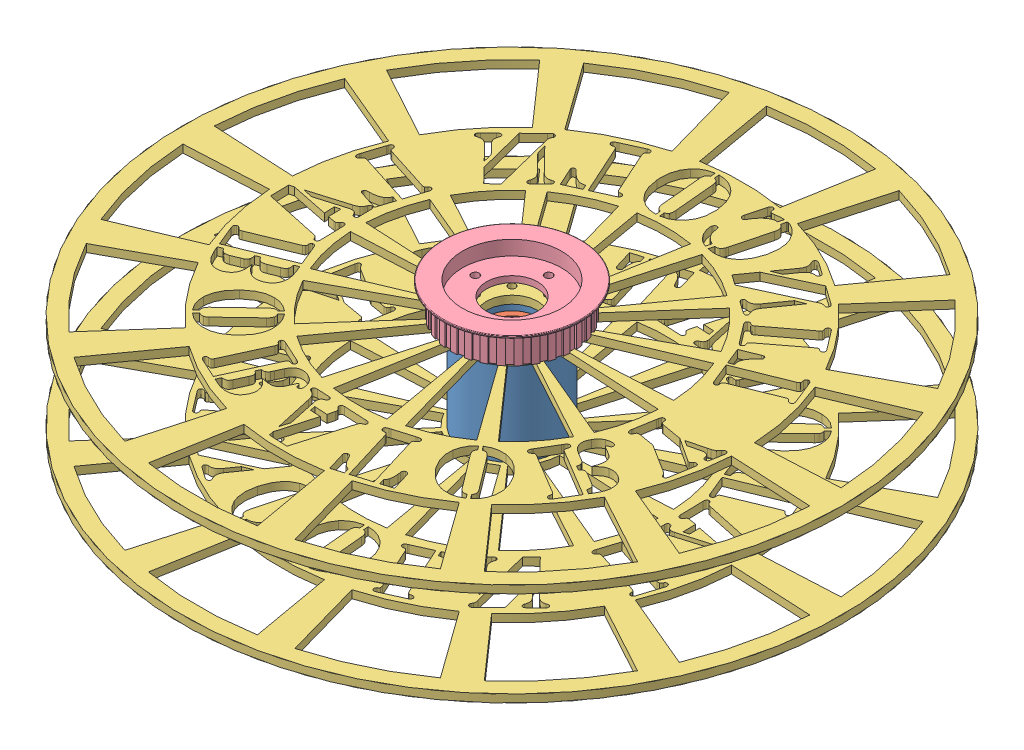
SolidWorks assembly Assembly_Spool, configuration Default. Lengths in mm.
Overall size (266.7 65.58 266.7).
6 component instances, 4 part files, 18 mates.
Components (placement in the parent):
- Spool_Hub-1: Spool_Hub [Default] at origin size (37.28 35.03 37.28)
- Bearing_ID6mm_OD22mm-1: Bearing_ID6mm_OD22mm [5972K501] at (0 6.025 0) x (1 0 0) z (0 1 0) size (22 22 7)
- Bearing_ID6mm_OD22mm-2: Bearing_ID6mm_OD22mm [5972K501] at (0 29.0063 0) x (1 0 0) z (0 1 0) size (22 22 7)
- Spool_Side_Plate-1: Spool_Side_Plate [Default] x (-1 0 0) z (0 -1 0) size (266.7 266.7 3.17)
- Spool_Side_Plate-2: Spool_Side_Plate [Default] at (0 38.2062 0) x (1 0 0) z (0 -1 0) size (266.7 266.7 3.17)
- Timing_Pulley-1: Timing_Pulley [Default] at (0 43.7625 0) x (0 1 0) z (-1 0 0) size (24.2 62.72 62.72)
Mates (geometry in assembly coordinates):
- Coincident1: coordinate: point of Spool_Hub-1; point of assembly
- Parallel1: parallel aligned: plane of Spool_Hub-1 through (0 0 0) normal (1 0 0); plane of assembly through (0 0 0) normal (1 0 0)
- InPlace1: in place: plane of Spool_Hub-1 through (0 0 0) normal (0 -1 0); plane of Spool_Side_Plate-1 through (0 0 0) normal (0 -1 0); moOrthogonalPlaneRef_w of Spool_Hub-1 through (0 0 0) normal (0 -1 0); unknown of Spool_Side_Plate-1; plane of Spool_Hub-1 through (0 0 0) normal (0 -1 0); line of Spool_Side_Plate-1 through (55 -55 0) axis (0 0 -1); plane of Spool_Hub-1 through (0 0 0) normal (0 -1 0); unknown of Spool_Side_Plate-1
- Coincident2: coincident aligned: plane of Spool_Hub-1; plane of Spool_Side_Plate-1
- Coincident3: coincident aligned: moOrthogonalPlaneRef_w of Spool_Hub-1 through (0 0 0) normal (0 0 -1); plane of Spool_Side_Plate-1
- Coincident4: coincident: moOrthogonalPlaneRef_w of Spool_Hub-1 through (0 0 0) normal (1 0 0); plane of Spool_Side_Plate-1
- Coincident5: coincident anti-aligned: plane of Spool_Hub-1 through (0 35.0312 0) normal (0 1 0); plane of Spool_Side_Plate-2 through (0 35.0312 0) normal (0 -1 0)
- Coincident6: coincident aligned: plane of Spool_Side_Plate-2 through (0 38.2062 0) normal (0 0 1); plane of assembly through (0 0 0) normal (0 0 1)
- Coincident20: coincident anti-aligned: plane of Spool_Side_Plate-2 through (0 38.2062 0) normal (0 1 0); plane of Timing_Pulley-1 through (0 38.2062 0) normal (0 -1 0)
- Coincident21: coincident anti-aligned: plane of Spool_Hub-1 through (0 9.525 0) normal (0 -1 0); plane of Bearing_ID6mm_OD22mm-1 through (0 9.525 -10.65) normal (0 1 0)
- Parallel2: parallel anti-aligned: plane of Bearing_ID6mm_OD22mm-1 through (0 6.025 0) normal (0 0 -1); plane of assembly through (0 0 0) normal (0 0 1)
- Concentric12: concentric aligned: cylinder of Spool_Hub-1 through (0 25.5063 0) axis (0 1 0) radius 11.049; cylinder of Bearing_ID6mm_OD22mm-2 through (0 32.5063 0) axis (0 1 0) radius 11
- Coincident23: coincident anti-aligned: plane of Spool_Hub-1 through (0 25.5063 0) normal (0 1 0); plane of Bearing_ID6mm_OD22mm-2 through (0 25.5063 -10.65) normal (0 -1 0)
- Parallel3: parallel anti-aligned: plane of Bearing_ID6mm_OD22mm-2 through (0 29.0063 0) normal (0 0 -1); plane of assembly through (0 0 0) normal (0 0 1)
- Concentric13: concentric anti-aligned: cylinder of Spool_Hub-1 through (0 9.525 0) axis (0 -1 0) radius 11.049; cylinder of Bearing_ID6mm_OD22mm-1 through (0 9.525 0) axis (0 1 0) radius 11
- Concentric14: concentric anti-aligned: cylinder of Spool_Hub-1 through (-14.8433 35.0312 0) axis (0 1 0) radius 1.25; cylinder of Spool_Side_Plate-2 through (-14.8433 38.2062 0) axis (0 -1 0) radius 1.4732
- Concentric15: concentric anti-aligned: cylinder of Spool_Side_Plate-2 through (0 38.2062 0) axis (0 -1 0) radius 10.3434; cylinder of Timing_Pulley-1 through (0 38.2062 0) axis (0 1 0) radius 10.3434
- Concentric16: concentric anti-aligned: cylinder of Spool_Side_Plate-2 through (0 38.2062 14.8433) axis (0 -1 0) radius 1.4732; cylinder of Timing_Pulley-1 through (0 38.2062 14.8433) axis (0 1 0) radius 1.575
